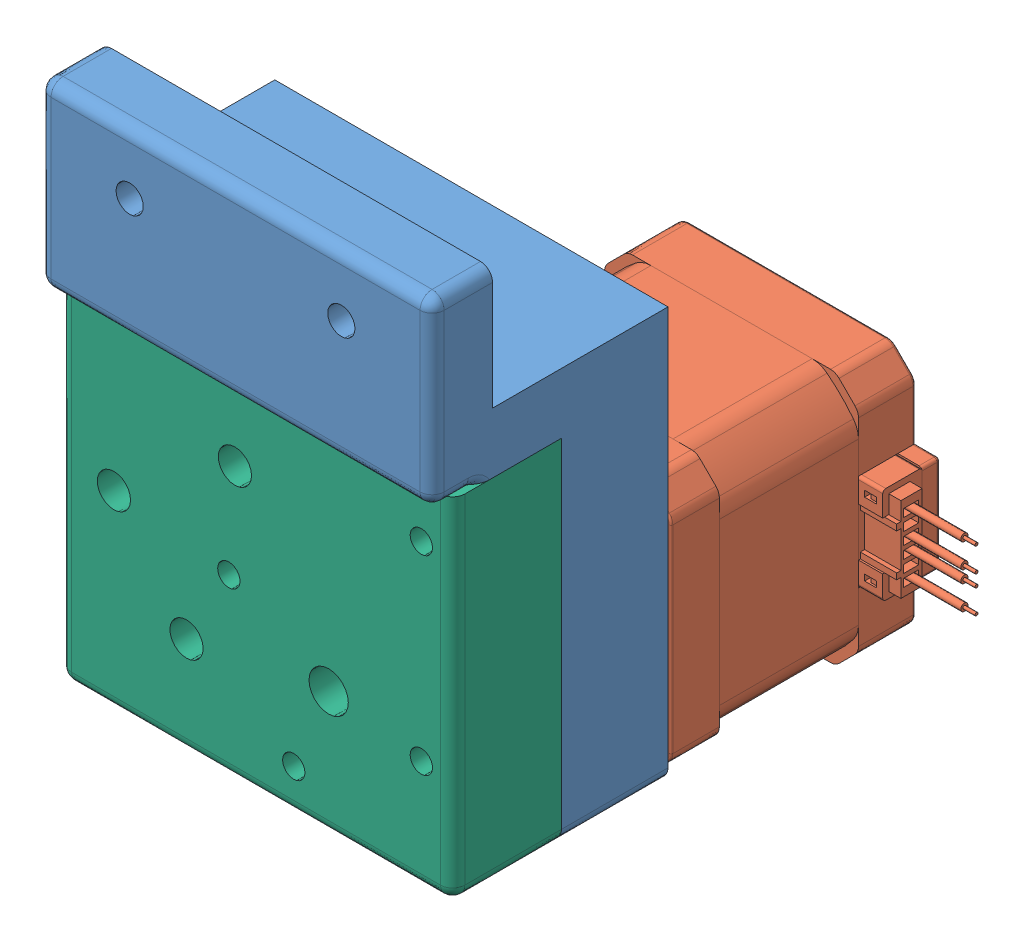
SolidWorks assembly MotorAssembly, configuration Default. Lengths in mm.
Overall size (82.35 88.5 79.65).
16 component instances, 6 part files, 14 mates.
Components (placement in the parent):
- MotorSupport-1: MotorSupport [Default] at (21.8927 42.8643 58.2584) size (65.5 88 39)
- nema_17_motor-1: nema_17_motor [Varsayılan] at (21.8927 42.8643 58.2584) x (0 -1 0) z (0 0 1) size (42 58.5 65.65)
- 1037396-1: 1037396 [Default] at (-1.6073 38.6171 72.6334) x (-0.568909 0.8224 0) z (-0.8224 -0.568909 0) size (18 9.45 18)
  - 1037396-IDLER PULLEY-1: 1037396-IDLER PULLEY [Default] at origin size (18 9.45 18)
  - 1037396-95-2Z BEARING, 9 mm OD, 5 mm ID, 3 mm WIDTH-1: 1037396-95-2Z BEARING, 9 mm OD, 5 mm ID, 3 mm WIDTH [DEFAULT] at (0 3.225 0) x (0.884042 0 0.467408) z (0 1 0) size (9 9 3)
  - 1037396-95-2Z BEARING, 9 mm OD, 5 mm ID, 3 mm WIDTH-2: 1037396-95-2Z BEARING, 9 mm OD, 5 mm ID, 3 mm WIDTH [DEFAULT] at (0 -3.225 0) x (-0.884042 0 -0.467408) z (0 -1 0) size (9 9 3)
- 1037396-2: 1037396 [Default] at (6.3927 67.3643 72.6334) x (0.987736 0.156132 0) z (-0.156132 0.987736 0) size (18 9.45 18)
  - 1037396-IDLER PULLEY-1: 1037396-IDLER PULLEY [Default] at origin size (18 9.45 18)
  - 1037396-95-2Z BEARING, 9 mm OD, 5 mm ID, 3 mm WIDTH-1: 1037396-95-2Z BEARING, 9 mm OD, 5 mm ID, 3 mm WIDTH [DEFAULT] at (0 3.225 0) x (0.884042 0 0.467408) z (0 1 0) size (9 9 3)
  - 1037396-95-2Z BEARING, 9 mm OD, 5 mm ID, 3 mm WIDTH-2: 1037396-95-2Z BEARING, 9 mm OD, 5 mm ID, 3 mm WIDTH [DEFAULT] at (0 -3.225 0) x (-0.884042 0 -0.467408) z (0 -1 0) size (9 9 3)
- GT2_16T-1: GT2_16T [Конфигурация1] at (21.8927 42.8643 67.7584) x (0 0 1) z (-0.944142 -0.329538 0) size (15.5 13.9 13.9)
- 1037396-3: 1037396 [Default] at (-13.6073 53.8643 80.5834) x (0.999198 0.040048 0) z (-0.040048 0.999198 0) size (18 9.45 18)
  - 1037396-IDLER PULLEY-1: 1037396-IDLER PULLEY [Default] at origin size (18 9.45 18)
  - 1037396-95-2Z BEARING, 9 mm OD, 5 mm ID, 3 mm WIDTH-1: 1037396-95-2Z BEARING, 9 mm OD, 5 mm ID, 3 mm WIDTH [DEFAULT] at (0 3.225 0) x (0.884042 0 0.467408) z (0 1 0) size (9 9 3)
  - 1037396-95-2Z BEARING, 9 mm OD, 5 mm ID, 3 mm WIDTH-2: 1037396-95-2Z BEARING, 9 mm OD, 5 mm ID, 3 mm WIDTH [DEFAULT] at (0 -3.225 0) x (-0.884042 0 -0.467408) z (0 -1 0) size (9 9 3)
- MotorSupportCover-1: MotorSupportCover [Default] at (21.8927 42.8643 75.8584) size (65 58 18.47)
Mates (geometry in assembly coordinates):
- Concentric1: concentric aligned: cylinder of MotorSupport-1 through (21.8927 42.8643 65.2584) axis (0 0 -1) radius 12; circle of nema_17_motor-1
- Concentric4: concentric anti-aligned: cylinder of MotorSupport-1 through (6.3927 67.3643 65.2584) axis (0 0 -1) radius 2.75; cylinder of 1037396-2/1037396-95-2Z BEARING, 9 mm OD, 5 mm ID, 3 mm WIDTH-2 through (6.3927 67.3643 77.3584) axis (0 0 1) radius 2.5
- Concentric7: concentric anti-aligned: cylinder of nema_17_motor-1 through (21.8927 42.8643 83.2584) axis (0 0 -1) radius 2.5; cylinder of GT2_16T-1 through (21.8927 42.8643 67.7584) axis (0 0 1) radius 2.5
- Coincident12: coincident aligned: plane of nema_17_motor-1 through (21.8927 44.8643 83.2584) normal (0 0 1); plane of GT2_16T-1 through (21.8927 42.8643 83.2584) normal (0 0 1)
- Concentric9: concentric anti-aligned: cylinder of MotorSupport-1 through (-1.6073 38.6171 67.9084) axis (0 0 -1) radius 2.75; cylinder of 1037396-1/1037396-95-2Z BEARING, 9 mm OD, 5 mm ID, 3 mm WIDTH-2 through (-1.6073 38.6171 77.3584) axis (0 0 1) radius 2.5
- Coincident14: coincident anti-aligned: plane of MotorSupport-1 through (-1.6073 38.6171 67.9084) normal (0 0 1); plane of 1037396-1/1037396-IDLER PULLEY-1 through (-1.6073 38.6171 67.9084) normal (0 0 -1)
- Concentric10: concentric anti-aligned: cylinder of MotorSupport-1 through (-13.6073 53.8643 67.9084) axis (0 0 -1) radius 2.75; cylinder of 1037396-3/1037396-95-2Z BEARING, 9 mm OD, 5 mm ID, 3 mm WIDTH-2 through (-13.6073 53.8643 85.3084) axis (0 0 1) radius 2.5
- Coincident16: coincident anti-aligned: plane of MotorSupport-1 through (6.3927 67.3643 67.9084) normal (0 0 1); plane of 1037396-2/1037396-IDLER PULLEY-1 through (6.3927 67.3643 67.9084) normal (0 0 -1)
- Coincident17: coincident anti-aligned: plane of MotorSupport-1 through (-13.6073 53.8643 75.8584) normal (0 0 1); plane of 1037396-3/1037396-IDLER PULLEY-1 through (-13.6073 53.8643 75.8584) normal (0 0 -1)
- Coincident18: coincident anti-aligned: plane of MotorSupport-1 through (21.8927 42.8643 58.2584) normal (0 0 -1); plane of nema_17_motor-1 through (21.8927 42.8643 58.2584) normal (0 0 1)
- Concentric12: concentric anti-aligned: cylinder of MotorSupport-1 through (16.1219 29.2416 71.8584) axis (0 0 1) radius 2; cylinder of MotorSupportCover-1 through (16.1219 29.2416 85.8584) axis (0 0 -1) radius 1.85
- Concentric13: concentric anti-aligned: cylinder of MotorSupport-1 through (37.2149 71.9912 71.8584) axis (0 0 1) radius 2; cylinder of MotorSupportCover-1 through (37.2149 71.9912 85.8584) axis (0 0 -1) radius 1.85
- Coincident19: coincident anti-aligned: plane of MotorSupport-1 through (-13.6073 53.8643 75.8584) normal (0 0 1); plane of MotorSupportCover-1 through (40.3927 24.3643 75.8584) normal (0 0 -1)
- Concentric14: concentric anti-aligned: cylinder of MotorSupport-1 through (37.3927 27.3643 64.7584) axis (0 0 -1) radius 1.8; cylinder of nema_17_motor-1 through (37.3927 27.3643 58.2584) axis (0 0 1) radius 1.25
